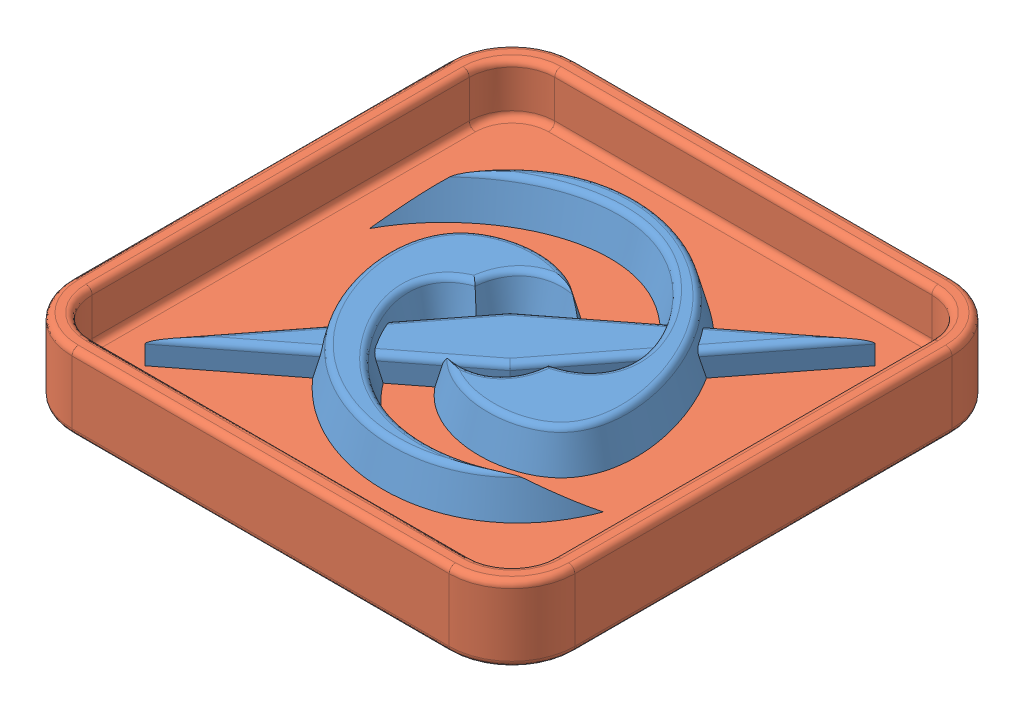
SolidWorks assembly Assem2, configuration Default. Lengths in mm.
Overall size (40 6 40).
2 component instances, 2 part files, 2 mates.
Components (placement in the parent):
- Pulsar-1: Pulsar [Default] at (9.3068 20.0915 39.3583) size (29.57 3.58 30.05)
- Tile-1: Tile [Default] at (9.7068 18.0915 39.6093) size (40 6 40)
Mates (geometry in assembly coordinates):
- Coincident1: coincident anti-aligned: plane of Pulsar-1 through (9.3068 20.0915 39.3583) normal (0 -1 0); plane of Tile-1 through (-5.2932 20.0915 54.6093) normal (0 1 0)
- Coincident2: coincident aligned: line of Pulsar-1 through (-8.1932 20.0915 21.8583) axis (0 0 1); line of Tile-1 through (-8.1932 20.0915 24.6093) axis (0 0 1)
